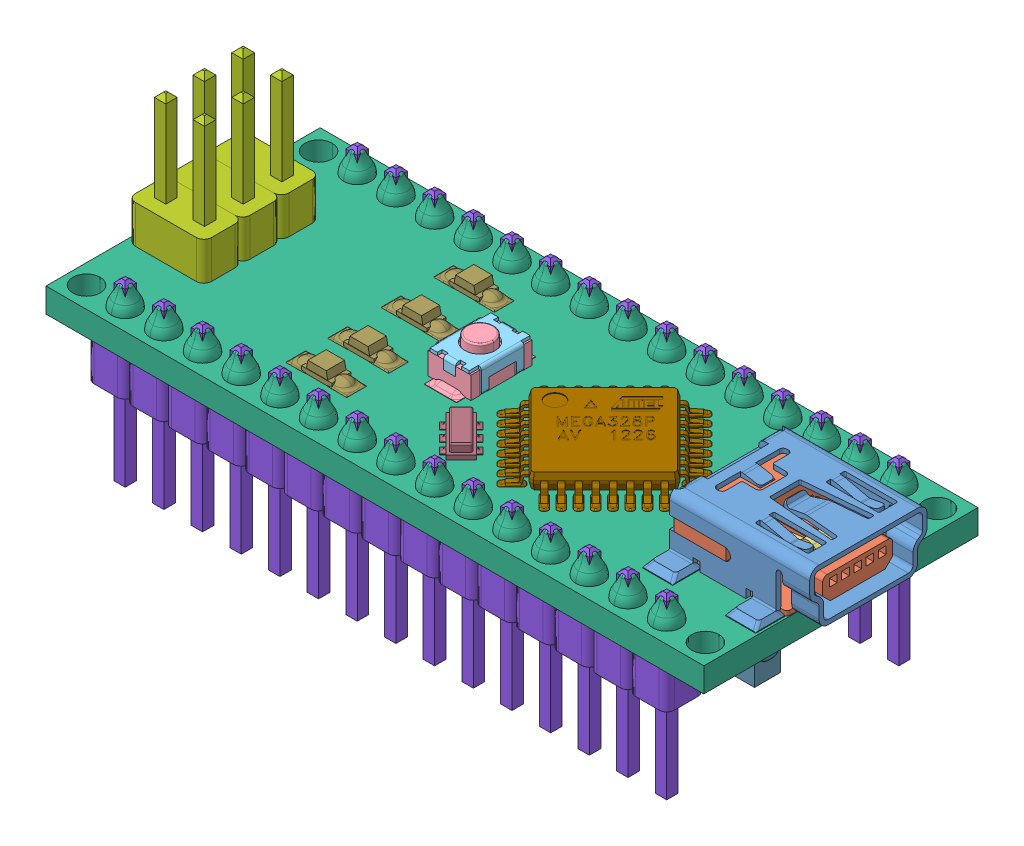
SolidWorks assembly arduino nano, configuration Default. Lengths in mm.
Overall size (45 18.6 18).
36 component instances, 18 part files, 0 mates.
Components (placement in the parent):
- arduino nano.STEP-1: arduino nano.STEP [Default] at origin size (45 18.6 18)
  - MINIUSB - MEASURED.STEP-1: MINIUSB - MEASURED.STEP [Default] at (38.98 1.65 -7.62) x (0 0 1) z (-1 0 0) size (10.9 4.8 10.4)
    - MINIUSBSHELL.STEP-1: MINIUSBSHELL.STEP [Default] at origin size (10.9 3.75 9.4)
    - MINIUSBCORE.STEP-1: MINIUSBCORE.STEP [Default] at (0 0 6.7) x (-1 0 0) z (0 0 -1) size (7.7 4.5 8.2)
    - MINI USB CONTACT.STEP-1: MINI USB CONTACT.STEP [Default] at (-1.6 0 5.7) x (-1 0 0) z (0 0 -1) size (0.51 2.55 9.4)
    - MINI USB CONTACT.STEP-2: MINI USB CONTACT.STEP [Default] at (-0.8 0 5.7) x (-1 0 0) z (0 0 -1) size (0.51 2.55 9.4)
    - MINI USB CONTACT.STEP-3: MINI USB CONTACT.STEP [Default] at (0 0 5.7) x (-1 0 0) z (0 0 -1) size (0.51 2.55 9.4)
    - MINI USB CONTACT.STEP-4: MINI USB CONTACT.STEP [Default] at (0.8 0 5.7) x (-1 0 0) z (0 0 -1) size (0.51 2.55 9.4)
    - MINI USB CONTACT.STEP-5: MINI USB CONTACT.STEP [Default] at (1.6 0 5.7) x (-1 0 0) z (0 0 -1) size (0.51 2.55 9.4)
  - reset button.STEP-1: reset button.STEP [Default] at (15.25 1.6 -8.05) x (0 0 -1) z (1 0 0) size (5.2 2.15 3)
    - reset core.STEP-1: reset core.STEP [Default] at origin size (5.2 2.15 2.8)
    - reset shell.STEP-1: reset shell.STEP [Default] at (0 1.65 0) x (0 0 1) z (-1 0 0) size (3 1.65 4)
  - nano-board.STEP-1: nano-board.STEP [Default] at origin size (43.2 4.6 18)
  - 2pin_header__02.STEP-1: 2pin_header__02.STEP [Default] at (-1.143 1.6 -7.62) size (5 11.75 2.54)
  - 2pin_header__02.STEP-2: 2pin_header__02.STEP [Default] at (-1.143 1.6 -5.08) size (5 11.75 2.54)
  - 2pin_header__02.STEP-3: 2pin_header__02.STEP [Default] at (-1.143 1.6 -10.16) size (5 11.75 2.54)
  - 15pin_header__.STEP-1: 15pin_header__.STEP [Default] x (0 0 1) z (1 0 0) size (2.54 11.75 38.1)
  - 15pin_header__.STEP-2: 15pin_header__.STEP [Default] at (0 0 -15.24) x (0 0 1) z (1 0 0) size (2.54 11.75 38.1)
  - atmega328.STEP-1: atmega328.STEP [Default] at (23.85 1.75 -7.62) x (-0.707107 0 0.707107) z (-0.707107 0 -0.707107) size (10 1.1 10)
  - ftdi FT232rl.STEP-1: ftdi FT232rl.STEP [Default] at (29.05 0 -7.67) x (0 0 -1) z (-1 0 0) size (9.25 1.9 10.2)
  - smt_resistor222.STEP-1: smt_resistor222.STEP [Default] at (21.86 0 -5.8) x (0 0 -1) z (-1 0 0) size (1.7 0.6 3.8)
  - smt_resistor222.STEP-2: smt_resistor222.STEP [Default] at (21.86 0 -9) x (0 0 -1) z (-1 0 0) size (1.7 0.6 3.8)
  - smt_resistor222.STEP-3: smt_resistor222.STEP [Default] at (36.75 0 -7.6) x (0 0 -1) z (-1 0 0) size (1.7 0.6 3.8)
  - smt_resistor222.STEP-4: smt_resistor222.STEP [Default] at (36.75 0 -12) x (0 0 -1) z (-1 0 0) size (1.7 0.6 3.8)
  - smt_resistor222.STEP-5: smt_resistor222.STEP [Default] at (8.2 0 -2.6) x (0 0 -1) z (-1 0 0) size (1.7 0.6 3.8)
  - led.STEP-1: led.STEP [Default] at (10.4 1.6 -2.8) size (4 0.85 1.47)
  - led.STEP-2: led.STEP [Default] at (10.4 1.6 -5.55) size (4 0.85 1.47)
  - led.STEP-3: led.STEP [Default] at (10.4 1.6 -12.5) size (4 0.85 1.47)
  - led.STEP-4: led.STEP [Default] at (10.4 1.6 -9.05) size (4 0.85 1.47)
  - 16mhz crystal - measured.STEP-1: 16mhz crystal - measured.STEP [Default] at (18.5113 1.6 -3.5541) x (0.707107 0 0.707107) z (-0.707107 0 0.707107) size (3.4 0.8 2)
  - cap106C.STEP-1: cap106C.STEP [Default] at (37.2 0 -3.3) x (0 0 1) z (1 0 0) size (1.7 1.81 4)
  - cap106C.STEP-2: cap106C.STEP [Default] at (7.9 0 -5.6) x (0 0 -1) z (-1 0 0) size (1.7 1.81 4)
  - nano - reg.STEP-1: nano - reg.STEP [Default] at (6.1 0 -10.16) x (0 0 -1) z (-1 0 0) size (6.5 1.69 8.3)
  - NANO DIODE.STEP-1: NANO DIODE.STEP [Default] at (11.43 0 -4.2) x (0 0 1) z (1 0 0) size (4.92 1.39 1.7)
  - 189 RESISTOR PACK.STEP-1: 189 RESISTOR PACK.STEP [Default] at (15.75 0 -10.85) x (0 0 1) z (1 0 0) size (3.2 0.46 3)
  - 102 RESISTOR PACK.STEP-1: 102 RESISTOR PACK.STEP [Default] at (15.75 0 -5.2) x (0 0 1) z (1 0 0) size (3.2 0.46 3)
